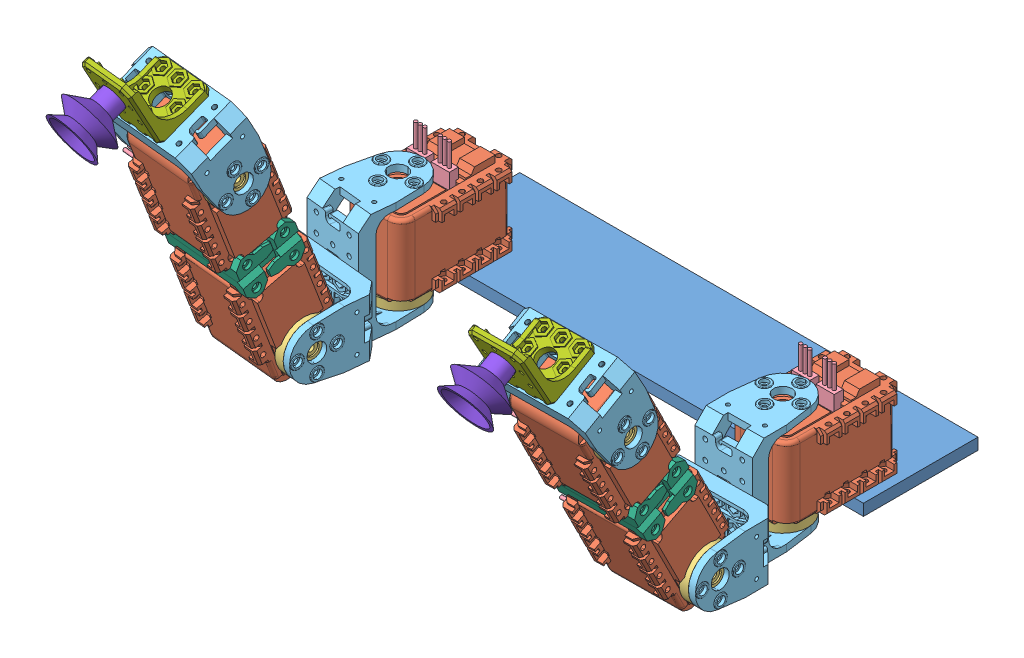
SolidWorks assembly Essai_double_bras, configuration Default. Lengths in mm.
Overall size (234.97 151.52 216.76).
47 component instances, 8 part files, 6 mates.
Components (placement in the parent):
- Plaque_fixation_test-1: Plaque_fixation_test [Default] at (-142.8503 -10.3701 26.574) size (200 5 50)
- Essai_bras_AX12_V1-1: Essai_bras_AX12_V1 [Défaut-_flexible1] at (143.8265 9.3274 23.8971) x (1 0 0) z (0 -1 0) size (56.89 186.06 146.96) (flexible)
  - servomoteur_ax-12-1: servomoteur_ax-12 [Default] at (-100 0 0) size (32 52.31 53.4)
    - AX-12_modif-1: AX-12_modif [Défaut] at (-2.6768 21.8769 -4.3025) size (32 50.06 38.01)
    - attache_ax-12-1: attache_ax-12 [Default] at (-2.6768 21.8769 12.6975) x (-0.301968 0.953318 0) z (0 0 1) size (22 22 4.7)
    - connecteur_AX-12-1: connecteur_AX-12 [Default] at (6.5732 8.6769 -17.5025) x (-1 0 0) z (0 -1 0) size (8 18.5 4)
    - connecteur_AX-12-2: connecteur_AX-12 [Default] at (-4.0768 8.6769 -17.5025) x (-1 0 0) z (0 -1 0) size (8 18.5 4)
  - F2-1: F2 [Défaut] at (-102.6768 21.8769 -4.3025) x (0 0 1) z (0.009533 0.999955 0) size (48.81 25 37)
  - servomoteur_ax-12-2: servomoteur_ax-12 [Default] at (-97.6306 99.8642 -50.9612) x (-0.008504 -0.892037 -0.451882) z (0.999955 -0.009533 0) size (32 52.31 53.4)
    - AX-12_modif-1: AX-12_modif [Défaut] at (-2.6768 21.8769 -4.3025) size (32 50.06 38.01)
    - attache_ax-12-1: attache_ax-12 [Default] at (-2.6768 21.8769 12.6975) x (-0.301968 0.953318 0) z (0 0 1) size (22 22 4.7)
    - connecteur_AX-12-1: connecteur_AX-12 [Default] at (6.5732 8.6769 -17.5025) x (-1 0 0) z (0 -1 0) size (8 18.5 4)
    - connecteur_AX-12-2: connecteur_AX-12 [Default] at (-4.0768 8.6769 -17.5025) x (-1 0 0) z (0 -1 0) size (8 18.5 4)
  - servomoteur_ax-12-3: servomoteur_ax-12 [Default] at (-97.7617 86.1066 -14.6088) x (0.008504 0.892037 0.451882) z (0.999955 -0.009533 0) size (32 52.31 53.4)
    - AX-12_modif-1: AX-12_modif [Défaut] at (-2.6768 21.8769 -4.3025) size (32 50.06 38.01)
    - attache_ax-12-1: attache_ax-12 [Default] at (-2.6768 21.8769 12.6975) x (-0.301968 0.953318 0) z (0 0 1) size (22 22 4.7)
    - connecteur_AX-12-1: connecteur_AX-12 [Default] at (6.5732 8.6769 -17.5025) x (-1 0 0) z (0 -1 0) size (8 18.5 4)
    - connecteur_AX-12-2: connecteur_AX-12 [Default] at (-4.0768 8.6769 -17.5025) x (-1 0 0) z (0 -1 0) size (8 18.5 4)
  - F2-2: F2 [Défaut] at (-101.8159 112.1783 -69.2675) x (0.999955 -0.009533 0) z (0.004673 0.490133 -0.871635) size (48.81 25 37)
  - F2-3: F2 [Défaut] at (-102.1811 73.8745 3.6975) x (-0.999955 0.009533 0) z (-0.009533 -0.999955 0) size (48.81 25 37)
  - F3-1: F3 [Défaut] at (-102.0019 92.6696 -32.9658) x (-0.008504 -0.892037 -0.451882) z (0.999955 -0.009533 0) size (25 9 38)
  - F3-2: F3 [Défaut] at (-102.0019 92.6696 -32.9658) x (0.008504 0.892037 0.451882) z (0.999955 -0.009533 0) size (25 9 38)
  - F9ORG-1: F9ORG [Défaut] at (-101.5905 135.8167 -85.8031) x (0.00831 0.871596 0.490155) z (-0.004673 -0.490133 0.871635) size (24 24 30)
  - ventouse_coval_VSA22_M5-1: ventouse_coval_VSA22_M5 [Default] at (-101.3439 161.6896 -93.0512) x (0.921593 -0.196902 0.334508) z (0.388068 0.448944 -0.804893) size (24 19 24)
- Essai_bras_AX12_V1-2: Essai_bras_AX12_V1 [Défaut-_flexible2] at (-124.1735 9.3274 23.8971) x (1 0 0) z (0 -1 0) size (63.21 174.07 150.41) (flexible)
  - servomoteur_ax-12-1: servomoteur_ax-12 [Default] at origin size (32 52.31 53.4)
    - AX-12_modif-1: AX-12_modif [Défaut] at (-2.6768 21.8769 -4.3025) size (32 50.06 38.01)
    - attache_ax-12-1: attache_ax-12 [Default] at (-2.6768 21.8769 12.6975) x (-0.301968 0.953318 0) z (0 0 1) size (22 22 4.7)
    - connecteur_AX-12-1: connecteur_AX-12 [Default] at (6.5732 8.6769 -17.5025) x (-1 0 0) z (0 -1 0) size (8 18.5 4)
    - connecteur_AX-12-2: connecteur_AX-12 [Default] at (-4.0768 8.6769 -17.5025) x (-1 0 0) z (0 -1 0) size (8 18.5 4)
  - F2-1: F2 [Défaut] at (-2.6768 21.8769 -4.3025) x (0 0 1) z (-0.098322 0.995155 0) size (48.81 25 37)
  - servomoteur_ax-12-2: servomoteur_ax-12 [Default] at (-5.4049 93.2487 -53.6869) x (0.092403 -0.935247 -0.341722) z (0.995155 0.098322 0) size (32 52.31 53.4)
    - AX-12_modif-1: AX-12_modif [Défaut] at (-2.6768 21.8769 -4.3025) size (32 50.06 38.01)
    - attache_ax-12-1: attache_ax-12 [Default] at (-2.6768 21.8769 12.6975) x (-0.301968 0.953318 0) z (0 0 1) size (22 22 4.7)
    - connecteur_AX-12-1: connecteur_AX-12 [Default] at (6.5732 8.6769 -17.5025) x (-1 0 0) z (0 -1 0) size (8 18.5 4)
    - connecteur_AX-12-2: connecteur_AX-12 [Default] at (-4.0768 8.6769 -17.5025) x (-1 0 0) z (0 -1 0) size (8 18.5 4)
  - servomoteur_ax-12-3: servomoteur_ax-12 [Default] at (-4.4902 83.991 -15.9477) x (-0.092403 0.935247 0.341722) z (0.995155 0.098322 0) size (32 52.31 53.4)
    - AX-12_modif-1: AX-12_modif [Défaut] at (-2.6768 21.8769 -4.3025) size (32 50.06 38.01)
    - attache_ax-12-1: attache_ax-12 [Default] at (-2.6768 21.8769 12.6975) x (-0.301968 0.953318 0) z (0 0 1) size (22 22 4.7)
    - connecteur_AX-12-1: connecteur_AX-12 [Default] at (6.5732 8.6769 -17.5025) x (-1 0 0) z (0 -1 0) size (8 18.5 4)
    - connecteur_AX-12-2: connecteur_AX-12 [Default] at (-4.0768 8.6769 -17.5025) x (-1 0 0) z (0 -1 0) size (8 18.5 4)
  - F2-2: F2 [Défaut] at (-10.669 102.7687 -73.3321) x (0.995155 0.098322 0) z (-0.045644 0.46198 -0.885715) size (48.81 25 37)
  - F2-3: F2 [Défaut] at (-7.7895 73.6249 3.6975) x (-0.995155 -0.098322 0) z (0.098322 -0.995155 0) size (48.81 25 37)
  - F3-1: F3 [Défaut] at (-9.1923 87.8227 -34.954) x (0.092403 -0.935247 -0.341722) z (0.995155 0.098322 0) size (25 9 38)
  - F3-2: F3 [Défaut] at (-9.1923 87.8227 -34.954) x (-0.092403 0.935247 0.341722) z (0.995155 0.098322 0) size (25 9 38)
  - F9ORG-1: F9ORG [Défaut] at (-12.9443 125.798 -90.5578) x (-0.087085 0.881423 0.46423) z (0.045644 -0.46198 0.885715) size (24 24 30)
  - ventouse_coval_VSA22_M5-1: ventouse_coval_VSA22_M5 [Default] at (-15.4661 151.3227 -98.566) x (0.08027 0.470693 -0.878638) z (-0.992962 -0.039253 -0.111743) size (24 19 24)
Mates (geometry in assembly coordinates):
- Coïncidente23: coincident anti-aligned: plane of Plaque_fixation_test-1 through (-142.8503 -5.3701 -23.426) normal (0 1 0); plane of Essai_bras_AX12_V1-1/servomoteur_ax-12-1/AX-12_modif-1 through (30.7497 -5.3701 12.784) normal (0 -1 0)
- Coïncidente24: coincident aligned: plane of Plaque_fixation_test-1 through (-142.8503 -5.3701 26.574) normal (0 0 1); plane of Essai_bras_AX12_V1-1/servomoteur_ax-12-1/AX-12_modif-1 through (57.2361 30.2699 26.574) normal (0 0 1)
- Coïncidente25: coincident aligned: plane of Plaque_fixation_test-1 through (57.1497 -5.3701 26.574) normal (1 0 0); plane of Essai_bras_AX12_V1-1/servomoteur_ax-12-1/AX-12_modif-1 through (57.1497 -1.4565 43.186) normal (1 0 0)
- Coïncidente26: coincident aligned: plane of Essai_bras_AX12_V1-1/servomoteur_ax-12-1/AX-12_modif-1 through (47.2497 28.2939 8.774) normal (0 0 -1); plane of Essai_bras_AX12_V1-2/servomoteur_ax-12-1/AX-12_modif-1 through (-120.7503 28.2939 8.774) normal (0 0 -1)
- Coïncidente27: coincident anti-aligned: plane of Plaque_fixation_test-1 through (-142.8503 -5.3701 -23.426) normal (0 1 0); plane of Essai_bras_AX12_V1-2/servomoteur_ax-12-1/AX-12_modif-1 through (-137.2503 -5.3701 12.784) normal (0 -1 0)
- Coïncidente28: coincident aligned: plane of Plaque_fixation_test-1 through (-142.8503 -5.3701 26.574) normal (-1 0 0); plane of Essai_bras_AX12_V1-2/servomoteur_ax-12-1/AX-12_modif-1 through (-142.8503 -1.4565 11.362) normal (-1 0 0)
